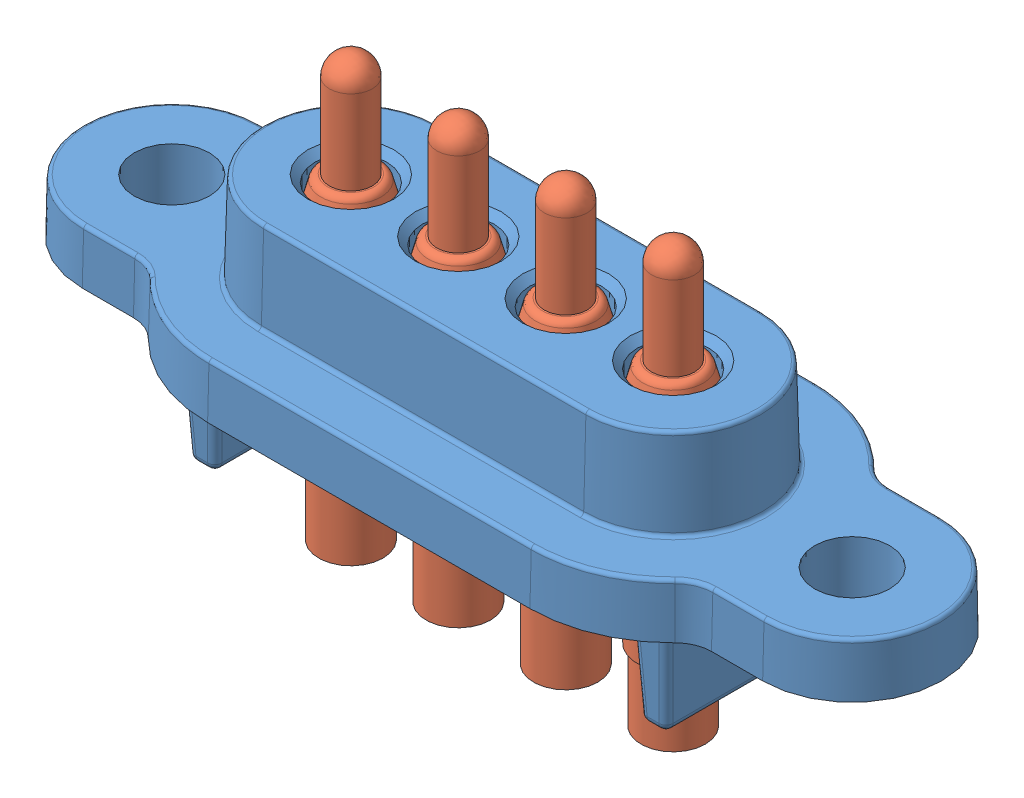
SolidWorks assembly SWIFT DOCK MINI-4-SC, configuration Défaut. Lengths in mm.
Overall size (24 11.8 8).
5 component instances, 2 part files, 0 mates.
Components (placement in the parent):
- body_4 hole_mini-1: body_4 hole_mini [Défaut] at origin size (24 6.8 8)
- contact_sd_mini-1: contact_sd_mini [Défaut] x (1 0 0) z (0 1 0) size (2.35 2.35 11.8)
- contact_sd_mini-2: contact_sd_mini [Défaut] at (3 0 0) x (1 0 0) z (0 1 0) size (2.35 2.35 11.8)
- contact_sd_mini-3: contact_sd_mini [Défaut] at (6 0 0) x (1 0 0) z (0 1 0) size (2.35 2.35 11.8)
- contact_sd_mini-4: contact_sd_mini [Défaut] at (9 0 0) x (1 0 0) z (0 1 0) size (2.35 2.35 11.8)
